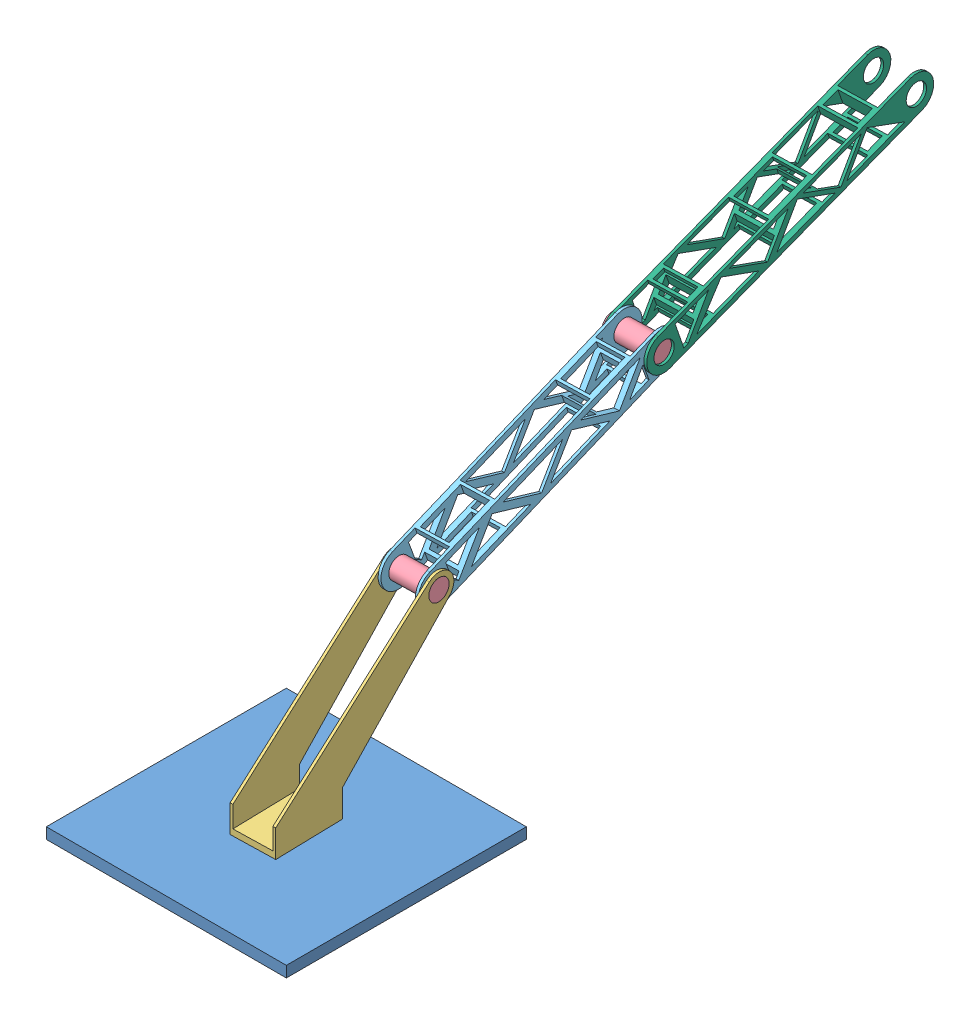
SolidWorks assembly Ensamblaje1, configuration Predeterminado. Lengths in mm.
Overall size (350 524.73 1116.98).
7 component instances, 6 part files, 12 mates.
Components (placement in the parent):
- base-1: base [Predeterminado] at (-17.4349 -55.9948 350) size (350 16 350)
- balero-1: balero [Predeterminado] at (-17.4349 -54.9948 350) size (45.3 15 45.3)
- brazo_0-1: brazo_0 [Predeterminado] at (-52.424 -19.9948 350.8718) x (0.99969 0 -0.024908) z (0.024908 0 0.99969) size (65 253.07 266.56)
- perno-1: perno [Predeterminado] at (10.2182 175.7072 155.0601) x (0.024908 0 0.99969) z (-0.99969 0 0.024908) size (30.4 30.4 70)
- brazo_1-1: brazo_1 [Predeterminado] at (-54.9566 239.3608 -11.7376) x (0.023299 -0.353631 0.935095) z (0.99969 0 -0.024908) size (414 54 57)
- Brazo_2-1: Brazo_2 [Predeterminado] at (-0.3701 369.3027 -370.2729) x (-0.99969 0 0.024908) z (-0.0235 0.331442 -0.943183) size (65 52 452)
- perno-2: perno [Predeterminado] at (-2.1681 303.0144 -181.4744) x (0.024402 -0.20062 0.979365) z (-0.99969 0 0.024908) size (30.4 30.4 70)
Mates (geometry in assembly coordinates):
- Concéntrica1: concentric aligned: cylinder of base-1 through (-17.4349 -39.9948 350) axis (0 -1 0) radius 22.75; cylinder of balero-1 through (-17.4349 -39.9948 350) axis (0 -1 0) radius 22.65
- Coincidente1: coincident aligned: plane of base-1 through (-17.4349 -39.9948 350) normal (0 1 0); plane of balero-1 through (-17.4349 -39.9948 350) normal (0 1 0)
- Concéntrica2: concentric anti-aligned: cylinder of balero-1 through (-17.4349 -39.9948 350) axis (0 -1 0) radius 10.75; cylinder of brazo_0-1 through (-17.4349 -54.9948 350) axis (0 1 0) radius 10.7
- Coincidente2: coincident anti-aligned: plane of base-1 through (-17.4349 -39.9948 350) normal (0 1 0); plane of brazo_0-1 through (16.3089 -39.9948 299.1437) normal (0 -1 0)
- Concéntrica3: concentric anti-aligned: cylinder of brazo_0-1 through (12.7174 175.7072 154.9978) axis (-0.99969 0 0.024908) radius 15.25; cylinder of perno-1 through (-59.7601 175.7072 156.8037) axis (0.99969 0 -0.024908) radius 15.2
- Concéntrica4: concentric anti-aligned: cylinder of perno-1 through (-59.7601 175.7072 156.8037) axis (0.99969 0 -0.024908) radius 15.2; cylinder of brazo_1-1 through (6.2194 175.7072 155.1597) axis (-0.99969 0 0.024908) radius 15.25
- Coincidente4: coincident anti-aligned: plane of brazo_0-1 through (5.6623 -30.9948 132.7996) normal (-0.99969 0 0.024908); plane of brazo_1-1 through (6.2194 175.7072 155.1597) normal (0.99969 0 -0.024908)
- Concéntrica5: concentric anti-aligned: cylinder of brazo_1-1 through (-2.1681 303.0144 -181.4744) axis (-0.99969 0 0.024908) radius 15.25; cylinder of perno-2 through (-72.1464 303.0144 -179.7308) axis (0.99969 0 -0.024908) radius 15.2
- Concéntrica6: concentric anti-aligned: cylinder of brazo_1-1 through (-2.1681 303.0144 -181.4744) axis (-0.99969 0 0.024908) radius 15.25; cylinder of Brazo_2-1 through (-65.6484 303.0144 -179.8927) axis (0.99969 0 -0.024908) radius 15.25
- Coincidente5: coincident anti-aligned: plane of brazo_1-1 through (6.2194 175.7072 155.1597) normal (0.99969 0 -0.024908); plane of Brazo_2-1 through (-3.6524 286.8528 -241.05) normal (-0.99969 0 0.024908)
- Coincidente6: coincident anti-aligned: plane of brazo_1-1 through (6.2194 175.7072 155.1597) normal (0.99969 0 -0.024908); circle of perno-2
- Coincidente8: coincident aligned: plane of brazo_0-1 through (10.2182 175.7072 155.0601) normal (0.99969 0 -0.024908); plane of perno-1 through (10.2182 175.7072 155.0601) normal (0.99969 0 -0.024908)
